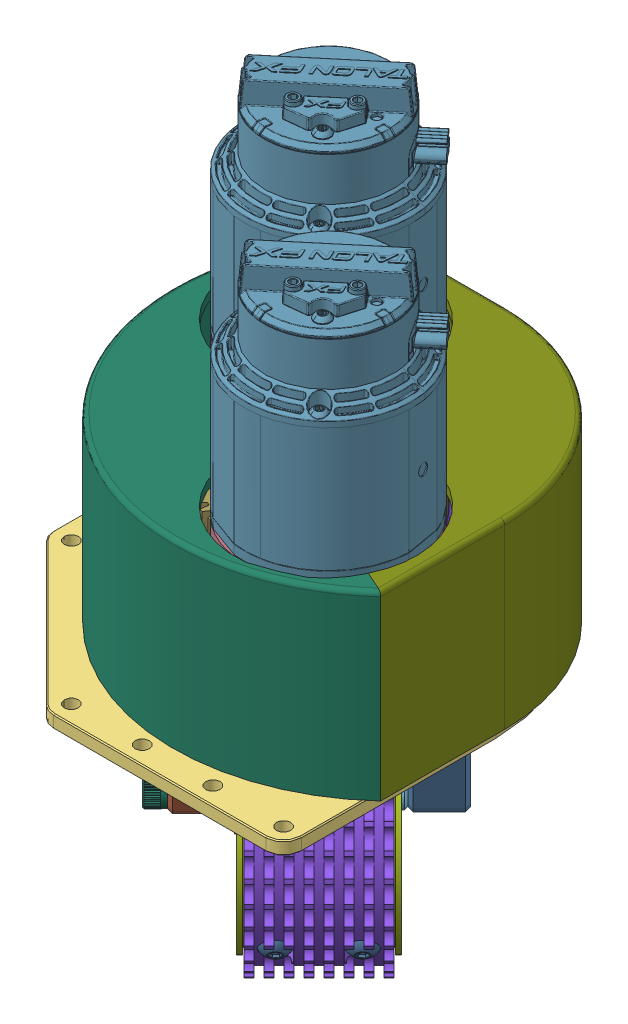
SolidWorks assembly swerve L2 with falcons, configuration Default. Lengths in mm.
Overall size (147.63 243.19 159.4).
89 component instances, 52 part files, 14 mates.
Components (placement in the parent):
- MK2 Steering Shaft V3 Assembly-1: MK2 Steering Shaft V3 Assembly [Default] at (-32.284 151.0849 -48.5468) x (-0.87791 0 -0.478826) z (0.478826 0 -0.87791) size (17.78 55.56 17.78)
  - MK2 Steering Shaft V3-1: MK2 Steering Shaft V3 [Default] at origin size (16.51 55.56 16.51)
  - MK2 Steering Shaft V3, Pulley Flange-1: MK2 Steering Shaft V3, Pulley Flange [Default] at (0 -51.0159 0) size (17.78 1.85 17.78)
- CANcoder Assembly-1: CANcoder Assembly [Default] at (0 132.454 0) x (-0.731354 0 -0.681998) z (0 1 0) size (21.75 26.91 13.62)
  - CANcoder Top Housing-1: CANcoder Top Housing [Default] at origin size (21.53 26.79 8.94)
  - CANcoder PCA-1: CANcoder PCA [Default] at (0 0 22.3055) size (15.93 23.27 3.19)
  - CANcoder Screw-1: CANcoder Screw [Default] at origin size (4.24 4.24 13.04)
  - CANcoder Bottom Housing-1: CANcoder Bottom Housing [Default] at origin size (21.75 26.91 6.46)
- MK4 Billet Wheel Assembly-1: MK4 Billet Wheel Assembly [Default] at (0 50.8 0) x (0.707107 0 -0.707107) z (-0.707107 0 -0.707107) size (42.28 100.26 100.13)
  - Wheel, SDS, Nitrile Tread, 4in X 1.5in, Bearing Bore(Default)-1: Wheel, SDS, Nitrile Tread, 4in X 1.5in, Bearing Bore(Default) [Default] at origin size (42.28 88.9 88.9)
  - Tread, Blue Nitrile 4in X 1.5in-1: Tread, Blue Nitrile 4in X 1.5in [Default] at origin size (38.1 100.26 100.13)
  - Screw, 10-32 X .75, Button, 91255A269-1: Screw, 10-32 X .75, Button, 91255A269 [Default] at (-4.826 0 -20.6375) x (0 -0.966455 -0.256836) z (-1 0 0) size (9.17 9.17 22.13)
  - Screw, 10-32 X .75, Button, 91255A269-2: Screw, 10-32 X .75, Button, 91255A269 [Default] at (-4.826 17.8726 -10.3187) x (0 -0.95104 -0.309068) z (-1 0 0) size (9.17 9.17 22.13)
  - Screw, 10-32 X .75, Button, 91255A269-3: Screw, 10-32 X .75, Button, 91255A269 [Default] at (-4.826 -17.8726 10.3187) x (0 -0.99925 -0.038711) z (-1 0 0) size (9.17 9.17 22.13)
  - Screw, 10-32 X .75, Button, 91255A269-4: Screw, 10-32 X .75, Button, 91255A269 [Default] at (-4.826 0 20.6375) x (0 -0.847203 -0.531269) z (-1 0 0) size (9.17 9.17 22.13)
  - Screw, 10-32 X .75, Button, 91255A269-5: Screw, 10-32 X .75, Button, 91255A269 [Default] at (-4.826 -17.8726 -10.3187) x (0 -0.986188 -0.165633) z (-1 0 0) size (9.17 9.17 22.13)
  - Screw, 10-32 X .75, Button, 91255A269-6: Screw, 10-32 X .75, Button, 91255A269 [Default] at (-4.826 17.8726 10.3187) x (0 -0.947988 -0.318305) z (-1 0 0) size (9.17 9.17 22.13)
  - Screw, 10-32 X .5, Button, 97763A232-1: Screw, 10-32 X .5, Button, 97763A232 [Default] at (11.1125 -40.6604 7.1695) x (-0.785325 0.107503 0.609678) z (0 -0.984808 0.173648) size (9.17 9.17 15.74)
  - Screw, 10-32 X .5, Button, 97763A232-2: Screw, 10-32 X .5, Button, 97763A232 [Default] at (-11.1125 -40.6604 7.1695) x (-0.636812 0.133886 0.759306) z (0 -0.984808 0.173648) size (9.17 9.17 15.74)
  - Screw, 10-32 X .5, Button, 97763A232-3: Screw, 10-32 X .5, Button, 97763A232 [Default] at (11.1125 20.6438 -35.7562) x (0.926716 -0.32542 -0.187881) z (0 0.5 -0.866025) size (9.17 9.17 15.74)
  - Screw, 10-32 X .5, Button, 97763A232-4: Screw, 10-32 X .5, Button, 97763A232 [Default] at (-11.1125 -40.6604 -7.1695) x (0.726076 -0.119403 0.677168) z (0 -0.984808 -0.173648) size (9.17 9.17 15.74)
  - Screw, 10-32 X .5, Button, 97763A232-5: Screw, 10-32 X .5, Button, 97763A232 [Default] at (11.1125 -40.6604 -7.1695) x (0.841108 -0.09392 0.53265) z (0 -0.984808 -0.173648) size (9.17 9.17 15.74)
  - Screw, 10-32 X .5, Button, 97763A232-6: Screw, 10-32 X .5, Button, 97763A232 [Default] at (-11.1125 20.6438 35.7562) x (0.515054 0.74232 -0.428579) z (0 0.5 0.866025) size (9.17 9.17 15.74)
  - Screw, 10-32 X .5, Button, 97763A232-7: Screw, 10-32 X .5, Button, 97763A232 [Default] at (-11.1125 20.6438 -35.7562) x (0.804058 -0.514897 -0.297276) z (0 0.5 -0.866025) size (9.17 9.17 15.74)
  - Screw, 10-32 X .5, Button, 97763A232-8: Screw, 10-32 X .5, Button, 97763A232 [Default] at (11.1125 20.6438 35.7562) x (0.200031 0.848523 -0.489895) z (0 0.5 0.866025) size (9.17 9.17 15.74)
- Gear, 17T, 20DP, .375Hex-1: Gear, 17T, 20DP, .375Hex [Default] at (19.8104 115.8932 -19.8104) x (0 1 0) z (0.984573 0 0.174975) size (12.6 23.99 24.09)
- Double Gear, 20DP, 27T, 50T-1: Double Gear, 20DP, 27T, 50T [Default] at (0 110.179 0) x (-0.825229 0 -0.564798) z (0 1 0) size (65.97 66.04 34.49)
- Gear, 32DP, 15T, Falcon Spline, am-4148-1: Gear, 32DP, 15T, Falcon Spline, am-4148 [Default] at (-27.051 149.4065 -30.4311) x (0 -1 0) z (-0.461391 0 0.887197) size (19.06 13.38 13.45)
- Gear, 20DP 14T, Falcon Spline, am-4147-1: Gear, 20DP 14T, Falcon Spline, am-4147 [Default] at (30.4311 146.2315 27.051) x (0 -1 0) z (-0.73357 0 -0.679614) size (12.71 19.97 20.32)
- Gear, 32DP, 32T, .375 Hex Bore-1: Gear, 32DP, 32T, .375 Hex Bore [Default] at (-32.284 138.5119 -48.5468) x (0 -1 0) z (0.475041 0 0.879964) size (15.88 26.9 26.9)
- Bevel Gear, 1545-1: Bevel Gear, 1545 [Default] at (19.8104 84.55 -19.8104) x (-0.174975 0 0.984573) z (0.984573 0 0.174975) size (25.18 14.25 25.31)
- Bevel Gear, 4515-1: Bevel Gear, 4515 [Default] at (11.9004 50.8 -11.9004) x (0 1 0) z (-0.707107 0 -0.707107) size (68.38 7.77 68.42)
- Bearing, A035XPO_SA035XPO-1: Bearing, A035XPO_SA035XPO [Default] at (0 95.3065 0) x (0.294255 0 -0.955727) z (0.955727 0 0.294255) size (101.6 6.35 101.6)
- Bearing, .375 ThunderHex, Flanged, 217-5829-1: Bearing, .375 ThunderHex, Flanged, 217-5829 [Default] at (19.8104 102.4503 -19.8104) x (-0.651134 0 -0.758963) z (0.758963 0 -0.651134) size (24.51 7.14 24.51)
- Bearing, R188ZZ, 217-3489-1: Bearing, R188ZZ, 217-3489 [Default] at (-32.284 97.6878 -48.5468) x (-0.351442 0 -0.93621) z (0.93621 0 -0.351442) size (12.7 4.76 12.7)
- Bearing, F689-ZZ-1: Bearing, F689-ZZ [Default] at (-32.284 147.694 -48.5468) x (-0.934655 0 -0.355556) z (-0.355556 0 0.934655) size (19 5 19)
- Bearing, 6802-1: Bearing, 6802 [Default] at (0 147.924 0) x (0.999998 0 0.002088) z (-0.002088 0 0.999998) size (24 5 24)
- Bearing, 6802-2: Bearing, 6802 [Default] at (0 118.1781 0) x (0.774702 0 -0.632327) z (0.632327 0 0.774702) size (24 5 24)
- Bearing, 6802-3: Bearing, 6802 [Default] at (0 138.5781 0) x (0.88578 0 0.464105) z (-0.464105 0 0.88578) size (24 5 24)
- Bearing, R6ZZ-1: Bearing, R6ZZ [Default] at (-12.5522 50.8 12.5522) x (0.172544 -0.969772 0.172544) z (-0.685732 -0.244014 -0.685732) size (22.23 7.14 22.23)
- Bearing, R8ZZ-1: Bearing, R8ZZ [Default] at (9.1464 50.8 -9.1464) x (-0.707107 0 -0.707107) z (0 -1 0) size (28.57 7.94 28.57)
- Bearing, 688-1: Bearing, 688 [Default] at (19.8104 71.5149 -19.8104) x (0 1 0) z (0.112572 0 0.993644) size (5 16 16)
- Spacer, #10 X 1.875, .3125 OD, 92510A554-1: Spacer, #10 X 1.875, .3125 OD, 92510A554 [Default] at (-50.9192 100.069 -39.1184) x (0.998998 0 0.044747) z (-0.044747 0 0.998998) size (7.94 47.62 7.94)
- Spacer, #10 X 1.875, .3125 OD, 92510A554-2: Spacer, #10 X 1.875, .3125 OD, 92510A554 [Default] at (-3.9576 100.069 -55.8311) x (-0.265756 0 0.96404) z (-0.96404 0 -0.265756) size (7.94 47.62 7.94)
- Spacer, #10 X 1.875, .3125 OD, 92510A554-3: Spacer, #10 X 1.875, .3125 OD, 92510A554 [Default] at (39.1184 100.069 50.9192) x (-0.625565 0 0.780172) z (-0.780172 0 -0.625565) size (7.94 47.62 7.94)
- Spacer, #10 X 1.875, .3125 OD, 92510A554-4: Spacer, #10 X 1.875, .3125 OD, 92510A554 [Default] at (55.8311 100.069 3.9576) x (-0.467329 0 0.884084) z (-0.884084 0 -0.467329) size (7.94 47.62 7.94)
- Screw, 10-32 X 2.5, 91251A355-1: Screw, 10-32 X 2.5, 91251A355 [Default] at (55.8311 90.544 3.9576) x (-0.993447 0 0.114295) z (0 -1 0) size (7.92 7.92 68.91)
- Screw, 10-32 X 2.5, 91251A355-2: Screw, 10-32 X 2.5, 91251A355 [Default] at (39.1184 160.4575 50.9192) x (-0.141029 0 0.990006) z (0 1 0) size (7.92 7.92 68.91)
- Screw, 10-32 X 2.5, 91251A355-3: Screw, 10-32 X 2.5, 91251A355 [Default] at (-3.9576 90.544 -55.8311) x (0.491596 0 0.870823) z (0 -1 0) size (7.92 7.92 68.91)
- Screw, 10-32 X 2.5, 91251A355-4: Screw, 10-32 X 2.5, 91251A355 [Default] at (-50.9192 160.4575 -39.1184) x (-0.935381 0 -0.353642) z (0 1 0) size (7.92 7.92 68.91)
- Screw, 10-32 X .25, Button, 91255A261-1: Screw, 10-32 X .25, Button, 91255A261 [Default] at (38.0763 89.5661 -38.0763) x (0.584943 0 0.811074) z (0 -1 0) size (9.17 9.17 9.36)
- Screw, 10-32 X .25, Button, 91255A261-2: Screw, 10-32 X .25, Button, 91255A261 [Default] at (-51.3558 89.5661 16.1924) x (0.968677 0 0.248324) z (0 -1 0) size (9.17 9.17 9.36)
- Screw, 10-32 X .25, Button, 91255A261-3: Screw, 10-32 X .25, Button, 91255A261 [Default] at (49.3819 89.5661 21.4718) x (0.746035 0 0.665906) z (0 -1 0) size (9.17 9.17 9.36)
- Screw, 10-32 X .25, Button, 91255A261-4: Screw, 10-32 X .25, Button, 91255A261 [Default] at (-21.4718 89.5661 -49.3819) x (0.421611 0 0.906777) z (0 -1 0) size (9.17 9.17 9.36)
- Screw, 10-32 X .25, Button, 91255A261-5: Screw, 10-32 X .25, Button, 91255A261 [Default] at (-16.1924 89.5661 51.3558) x (0.881355 0 0.472455) z (0 -1 0) size (9.17 9.17 9.36)
- Screw, 10-32 X .375, 91251A340-1: Screw, 10-32 X .375, 91251A340 [Default] at (-3.1828 160.394 -21.7438) x (0.723662 0 0.690155) z (0 1 0) size (7.92 7.92 14.86)
- Screw, 10-32 X .375, 91251A340-2: Screw, 10-32 X .375, 91251A340 [Default] at (21.7438 160.394 3.1828) x (0.945896 0 -0.324471) z (0 1 0) size (7.92 7.92 14.86)
- Screw, 12-24 X .625, Flat, 91253A282-1: Screw, 12-24 X .625, Flat, 91253A282 [Default] at (19.8104 123.31 -19.8104) x (-0.039412 0 -0.999223) z (0 1 0) size (10.72 10.72 16.41)
- Screw, .25-20 X 1 Socket, 91251A542-1: Screw, .25-20 X 1 Socket, 91251A542 [Default] at (-35.921 101.6565 7.1842) x (1 0 0) z (0 1 0) size (9.53 9.53 32.53)
- Screw, .25-20 X 1 Socket, 91251A542-2: Screw, .25-20 X 1 Socket, 91251A542 [Default] at (-7.1842 101.6565 35.921) x (1 0 0) z (0 1 0) size (9.53 9.53 32.53)
- Screw, .25-20 X .625, 91251A539-1: Screw, .25-20 X .625, 91251A539 [Default] at (0 126.2628 0) x (-0.984907 0 0.173085) z (0 1 0) size (9.53 9.53 22.95)
- Screw, .25-20 X .625, 91251A539-2: Screw, .25-20 X .625, 91251A539 [Default] at (35.921 83.3367 -7.1842) x (0.902722 0 0.430224) z (0 -1 0) size (9.53 9.53 22.95)
- Screw, .25-20 X .625, 91251A539-3: Screw, .25-20 X .625, 91251A539 [Default] at (7.1842 83.3367 -35.921) x (1 0 0) z (0 -1 0) size (9.53 9.53 22.95)
- Screw, Shoulder, .375 X 2.5, 5_16-18, 91259A634-1: Screw, Shoulder, .375 X 2.5, 5_16-18, 91259A634 [Default] at (-27.1653 50.8 27.1653) x (-0.636861 -0.434529 -0.636861) z (-0.307259 0.900658 -0.307259) size (14.29 83.05 14.29)
- Shim, 8mm ID X 14mm OD X .5mm Thick, 98055A115-1: Shim, 8mm ID X 14mm OD X .5mm Thick, 98055A115 [Default] at (19.8104 74.184 -19.8104) x (0.795246 0 -0.606287) z (0.606287 0 0.795246) size (14 1 14)
- MK3 Base Pulley-1: MK3 Base Pulley [Default] at (0 98.4815 0) x (0.707107 0 0.707107) z (-0.707107 0 0.707107) size (98.42 23.55 98.42)
- MK4 Intermediate Shaft(Default)-1: MK4 Intermediate Shaft(Default) [Default] at (19.8104 68.4142 -19.8104) x (0.643819 0 -0.765178) z (0.765178 0 0.643819) size (11.68 51.44 11.68)
- Wheel Mount B Gen2(Default)-1: Wheel Mount B Gen2(Default) [Default] at (21.5526 50.8 -21.5526) x (-0.707107 0 0.707107) z (-0.707107 0 -0.707107) size (15.88 49.27 57.15)
- Wheel Mount A(Default)-1: Wheel Mount A(Default) [Default] at (-21.5526 50.8 21.5526) x (-0.707107 0 0.707107) z (-0.707107 0 -0.707107) size (17.09 49.74 57.15)
- MK3 Plates(Both Plates With Chamfers)-1: MK3 Plates(Both Plates With Chamfers) [Default] at (0 92.1315 0) size (139.7 61.91 139.7)
- MK3 Center Column-1: MK3 Center Column [Default] at (0 113.1381 0) x (0.707107 0 0.707107) z (-0.707107 0 0.707107) size (17.27 40.32 17.27)
- MK4 Wheel Spacer-1: MK4 Wheel Spacer [Default] at (-10.0265 50.8 10.0265) x (-0.707107 0 0.707107) z (-0.270008 -0.924225 -0.270008) size (36.72 15.11 15.11)
- Screw, Falcon 500 Pinion-1: Screw, Falcon 500 Pinion [Default] at (-27.051 125.594 -30.4311) x (1 0 0) z (0 -1 0) size (8.18 8.18 15.18)
- Screw, Falcon 500 Pinion-2: Screw, Falcon 500 Pinion [Default] at (30.4311 125.594 27.051) x (0.982082 0 -0.188455) z (0 -1 0) size (8.18 8.18 15.18)
- Falcon Spacer .25-1: Falcon Spacer .25 [Default] at (30.4311 127.1815 27.051) x (0.98615 0 -0.165854) z (0.165854 0 0.98615) size (12.7 6.35 12.7)
- Falcon Spacer .125-1: Falcon Spacer .125 [Default] at (30.4311 146.2315 27.051) x (0.426668 0 0.904408) z (-0.904408 0 0.426668) size (12.7 3.17 12.7)
- Falcon Spacer .125-2: Falcon Spacer .125 [Default] at (-27.051 127.1815 -30.4311) x (-0.997535 0 0.070176) z (-0.070176 0 -0.997535) size (12.7 3.17 12.7)
- Falcon Spacer .0625-1: Falcon Spacer .0625 [Default] at (30.4311 125.594 27.051) x (0.953935 0 0.300012) z (-0.300012 0 0.953935) size (12.7 1.59 12.7)
- Falcon Spacer .0625-2: Falcon Spacer .0625 [Default] at (-27.051 125.594 -30.4311) x (-0.763171 0 -0.646197) z (0.646197 0 -0.763171) size (12.7 1.59 12.7)
- Screw, 3-48 X .1875, Pan Phillips, 90272A091-1: Screw, 3-48 X .1875, Pan Phillips, 90272A091 [Default] at (-7.2515 150.5515 -1.6741) x (-0.469771 0 0.882788) z (0 1 0) size (4.9 4.9 6.58)
- Screw, 3-48 X .1875, Pan Phillips, 90272A091-2: Screw, 3-48 X .1875, Pan Phillips, 90272A091 [Default] at (7.2515 150.5515 1.6741) x (1 0 0) z (0 1 0) size (4.9 4.9 6.58)
- magnet-1: magnet [Default] at (0 140.7598 0) x (0.899847 0 0.436205) z (-0.436205 0 0.899847) size (6.35 12.7 6.35)
- Belt, 320-5M-09-1: Belt, 320-5M-09 [Default] at (0 106.8063 0) x (0.832687 0 -0.553743) z (0.553743 0 0.832687) size (97.78 9 116.29)
- Motor Spacer editable and printable-1: Motor Spacer editable and printable [Default] at (30.4311 154.044 27.051) size (59.94 10.48 59.94)
- Motor, Falcon500(Shafts Shortened .25_)-3: Motor, Falcon500(Shafts Shortened .25_) [Default] at (28.1344 198.9196 21.124) x (0.984808 0 -0.173648) z (0 -1 0) size (60.01 60.01 110.41)
- Motor Spacer editable and printable-2: Motor Spacer editable and printable [Default] at (-27.051 154.044 -30.4311) size (59.94 10.48 59.94)
- Motor, Falcon500(Shafts Shortened .25_)-4: Motor, Falcon500(Shafts Shortened .25_) [Default] at (-29.3477 198.9196 -36.3581) x (0.984808 0 -0.173648) z (0 -1 0) size (60.01 60.01 110.41)
- Gearbox cover far pins-1: Gearbox cover far pins [Default] at (13.232 100.069 -13.232) size (132.26 65.2 132.23)
- Gearbox cover close pins side-1: Gearbox cover close pins side [Default] at (0 100.069 0.0001) size (111.22 65.09 111.22)
Mates (geometry in assembly coordinates):
- Coincident1: coincident anti-aligned: plane of MK3 Plates(Both Plates With Chamfers)-1 through (-27.051 154.044 -30.4311) normal (0 1 0); plane of Motor Spacer editable and printable-1 through (60.0221 154.044 27.051) normal (0 -1 0)
- Concentric1: concentric anti-aligned: cylinder of MK3 Plates(Both Plates With Chamfers)-1 through (30.4311 154.044 27.051) axis (0 -1 0) radius 9.5631; cylinder of Motor Spacer editable and printable-1 through (30.4311 151.885 27.051) axis (0 1 0) radius 9.506
- Coincident2: coincident anti-aligned: plane of Motor Spacer editable and printable-1 through (30.4311 161.9815 27.051) normal (0 1 0); plane of Motor, Falcon500(Shafts Shortened .25_)-3 through (24.3086 161.9815 19.7544) normal (0 -1 0)
- Concentric2: concentric anti-aligned: cylinder of Motor Spacer editable and printable-1 through (30.4311 161.9815 27.051) axis (0 1 0) radius 9.5504; cone of Motor, Falcon500(Shafts Shortened .25_)-3 through (30.4311 161.9815 27.051) axis (0 -1 0)
- Coincident3: coincident anti-aligned: plane of MK3 Plates(Both Plates With Chamfers)-1 through (-27.051 154.044 -30.4311) normal (0 1 0); plane of Motor Spacer editable and printable-2 through (2.54 154.044 -30.4311) normal (0 -1 0)
- Concentric3: concentric anti-aligned: cylinder of MK3 Plates(Both Plates With Chamfers)-1 through (-27.051 154.044 -30.4311) axis (0 -1 0) radius 9.5631; cylinder of Motor Spacer editable and printable-2 through (-27.051 161.9815 -30.4311) axis (0 1 0) radius 9.5504
- Coincident4: coincident anti-aligned: plane of Motor Spacer editable and printable-2 through (-27.051 161.9815 -30.4311) normal (0 1 0); plane of Motor, Falcon500(Shafts Shortened .25_)-4 through (-33.1736 161.9815 -37.7277) normal (0 -1 0)
- Concentric4: concentric anti-aligned: cylinder of Motor Spacer editable and printable-2 through (-27.051 161.9815 -30.4311) axis (0 1 0) radius 9.5504; cone of Motor, Falcon500(Shafts Shortened .25_)-4 through (-27.051 161.9815 -30.4311) axis (0 -1 0)
- Concentric5: concentric aligned: cylinder of Spacer, #10 X 1.875, .3125 OD, 92510A554-1 through (-50.9192 147.694 -39.1184) axis (0 -1 0) radius 3.9688; cylinder of Gearbox cover far pins-1 through (-50.9192 147.694 -39.1184) axis (0 -1 0) radius 4.7638
- Concentric6: concentric aligned: cylinder of Spacer, #10 X 1.875, .3125 OD, 92510A554-3 through (39.1184 147.694 50.9192) axis (0 -1 0) radius 3.9688; cylinder of Gearbox cover far pins-1 through (39.1184 147.694 50.9192) axis (0 -1 0) radius 4.7638
- Coincident5: coincident anti-aligned: plane of MK3 Plates(Both Plates With Chamfers)-1 through (-69.85 100.069 -57.15) normal (0 1 0); plane of Gearbox cover far pins-1 through (13.232 100.069 -13.232) normal (0 -1 0)
- Concentric7: concentric aligned: cylinder of Spacer, #10 X 1.875, .3125 OD, 92510A554-2 through (-3.9576 147.694 -55.8311) axis (0 -1 0) radius 3.9688; cylinder of Gearbox cover close pins side-1 through (-3.9576 147.694 -55.8311) axis (0 -1 0) radius 4.7638
- Concentric8: concentric aligned: cylinder of Spacer, #10 X 1.875, .3125 OD, 92510A554-4 through (55.8311 147.694 3.9576) axis (0 -1 0) radius 3.9688; cylinder of Gearbox cover close pins side-1 through (55.8312 147.694 3.9577) axis (0 -1 0) radius 4.7638
- Coincident6: coincident anti-aligned: plane of MK3 Plates(Both Plates With Chamfers)-1 through (-69.85 100.069 -57.15) normal (0 1 0); plane of Gearbox cover close pins side-1 through (0 100.069 0.0001) normal (0 -1 0)
